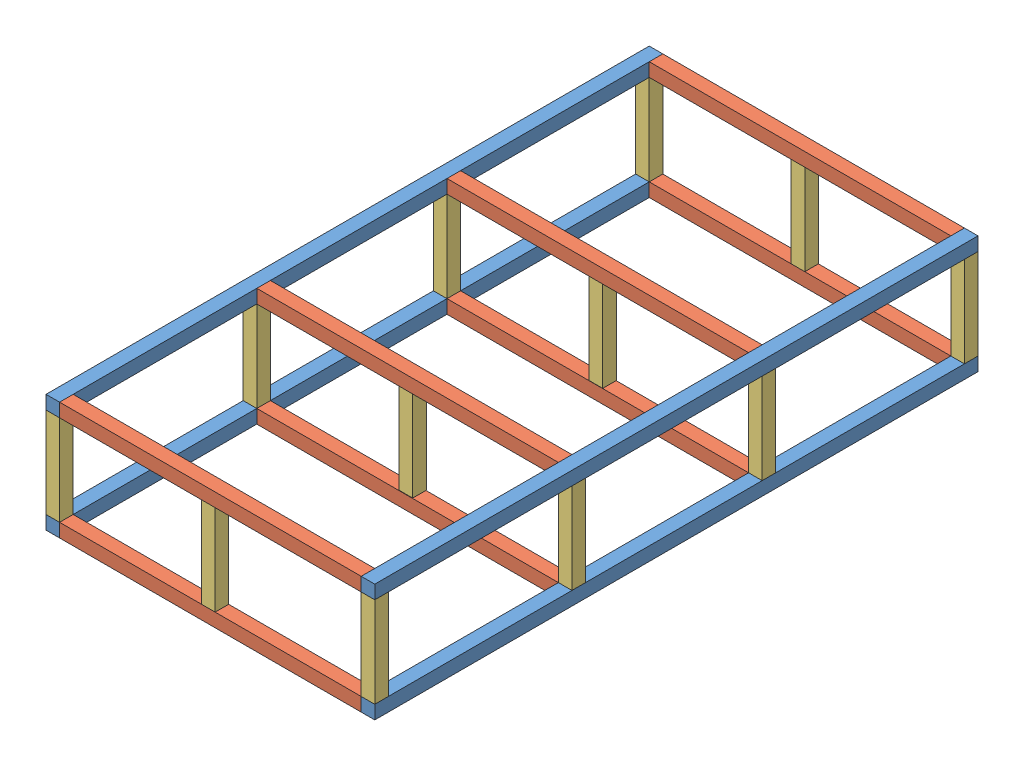
SolidWorks assembly New_assem, configuration Default. Lengths in mm.
Overall size (1090 390 2000).
24 component instances, 3 part files, 21 mates.
Components (placement in the parent):
- 4545_2000-1: 4545_2000 [Default] at (664.3232 958.4643 609.3143) size (45 45 2000)
- 4545_1000-1: 4545_1000 [Default] at (664.3232 958.4643 2564.3143) x (0 0 1) z (-1 0 0) size (45 45 1000)
- 4545_2000-2: 4545_2000 [Default] at (-380.6768 958.4643 609.3143) size (45 45 2000)
- 4545_1000-2: 4545_1000 [Default] at (664.3232 958.4643 609.3143) x (0 0 1) z (-1 0 0) size (45 45 1000)
- 4545_300-1: 4545_300 [Default] at (664.3232 1003.4643 2609.3143) x (1 0 0) z (0 1 0) size (45 45 300)
- 4545_300-2: 4545_300 [Default] at (-380.6768 1003.4643 2609.3143) x (1 0 0) z (0 1 0) size (45 45 300)
- 4545_300-3: 4545_300 [Default] at (664.3232 1003.4643 654.3143) x (1 0 0) z (0 1 0) size (45 45 300)
- 4545_300-4: 4545_300 [Default] at (-380.6768 1003.4643 654.3143) x (1 0 0) z (0 1 0) size (45 45 300)
- 4545_1000-3: 4545_1000 [Default] at (664.3232 1303.4643 609.3143) x (0 0 1) z (-1 0 0) size (45 45 1000)
- 4545_2000-3: 4545_2000 [Default] at (-380.6768 1303.4643 609.3143) size (45 45 2000)
- 4545_1000-4: 4545_1000 [Default] at (664.3232 1303.4643 2564.3143) x (0 0 1) z (-1 0 0) size (45 45 1000)
- 4545_2000-4: 4545_2000 [Default] at (664.3232 1303.4643 609.3143) size (45 45 2000)
- 4545_300-5: 4545_300 [Default] at (664.3232 1003.4643 1955.4889) x (1 0 0) z (0 1 0) size (45 45 300)
- 4545_300-6: 4545_300 [Default] at (664.3232 1003.4643 1324.9073) x (1 0 0) z (0 1 0) size (45 45 300)
- 4545_300-7: 4545_300 [Default] at (-380.6768 1003.4643 1324.9073) x (1 0 0) z (0 1 0) size (45 45 300)
- 4545_300-8: 4545_300 [Default] at (-380.6768 1003.4643 1955.4889) x (1 0 0) z (0 1 0) size (45 45 300)
- 4545_1000-5: 4545_1000 [Default] at (664.3232 958.4643 1910.4889) x (0 0 1) z (-1 0 0) size (45 45 1000)
- 4545_1000-6: 4545_1000 [Default] at (664.3232 958.4643 1279.9073) x (0 0 1) z (-1 0 0) size (45 45 1000)
- 4545_1000-7: 4545_1000 [Default] at (664.3232 1303.4643 1279.9073) x (0 0 1) z (-1 0 0) size (45 45 1000)
- 4545_1000-8: 4545_1000 [Default] at (664.3232 1303.4643 1910.4889) x (0 0 1) z (-1 0 0) size (45 45 1000)
- 4545_300-9: 4545_300 [Default] at (135.0671 1003.4643 654.3143) x (1 0 0) z (0 1 0) size (45 45 300)
- 4545_300-10: 4545_300 [Default] at (135.0671 1003.4643 1324.3143) x (1 0 0) z (0 1 0) size (45 45 300)
- 4545_300-11: 4545_300 [Default] at (135.0671 1003.4643 2609.3143) x (1 0 0) z (0 1 0) size (45 45 300)
- 4545_300-12: 4545_300 [Default] at (135.0671 1003.4643 1954.3143) x (1 0 0) z (0 1 0) size (45 45 300)
Mates (geometry in assembly coordinates):
- Coincident1: coincident anti-aligned: line of 4545_2000-1 through (664.3232 958.4643 2609.3143) axis (0 0 -1); line of 4545_1000-1 through (664.3232 958.4643 2564.3143) axis (0 0 1)
- Coincident2: coincident anti-aligned: line of 4545_2000-1 through (664.3232 1003.4643 2609.3143) axis (0 -1 0); line of 4545_1000-1 through (664.3232 958.4643 2609.3143) axis (0 1 0)
- Coincident3: coincident aligned: line of 4545_1000-1 through (-335.6768 958.4643 2609.3143) axis (0 1 0); line of 4545_2000-2 through (-335.6768 958.4643 2609.3143) axis (0 1 0)
- Coincident4: coincident aligned: line of 4545_1000-1 through (-335.6768 1003.4643 2609.3143) axis (0 0 -1); line of 4545_2000-2 through (-335.6768 1003.4643 2609.3143) axis (0 0 -1)
- Coincident5: coincident anti-aligned: line of 4545_2000-2 through (-335.6768 958.4643 609.3143) axis (0 1 0); line of 4545_1000-2 through (-335.6768 1003.4643 609.3143) axis (0 -1 0)
- Coincident6: coincident anti-aligned: line of 4545_2000-2 through (-335.6768 958.4643 2609.3143) axis (0 0 -1); line of 4545_1000-2 through (-335.6768 958.4643 609.3143) axis (0 0 1)
- Coincident8: coincident anti-aligned: plane of 4545_2000-1 through (664.3232 1003.4643 2609.3143) normal (0 1 0); plane of 4545_300-1 through (664.3232 1003.4643 2609.3143) normal (0 -1 0)
- Coincident9: coincident aligned: line of 4545_2000-1 through (709.3232 1003.4643 2609.3143) axis (0 0 -1); line of 4545_300-1 through (709.3232 1003.4643 2609.3143) axis (0 0 -1)
- Coincident10: coincident anti-aligned: line of 4545_2000-1 through (709.3232 1003.4643 2609.3143) axis (-1 0 0); line of 4545_300-1 through (664.3232 1003.4643 2609.3143) axis (1 0 0)
- Coincident11: coincident anti-aligned: plane of 4545_2000-1 through (664.3232 1003.4643 2609.3143) normal (0 1 0); plane of 4545_300-5 through (664.3232 1003.4643 1955.4889) normal (0 -1 0)
- Coincident12: coincident aligned: line of 4545_2000-1 through (709.3232 1003.4643 2609.3143) axis (0 0 -1); line of 4545_300-5 through (709.3232 1003.4643 1955.4889) axis (0 0 -1)
- Coincident13: coincident anti-aligned: plane of 4545_2000-1 through (664.3232 1003.4643 2609.3143) normal (0 1 0); plane of 4545_300-6 through (664.3232 1003.4643 1324.9073) normal (0 -1 0)
- Coincident14: coincident aligned: line of 4545_2000-1 through (709.3232 1003.4643 2609.3143) axis (0 0 -1); line of 4545_300-6 through (709.3232 1003.4643 1324.9073) axis (0 0 -1)
- Coincident17: coincident anti-aligned: plane of 4545_2000-2 through (-335.6768 958.4643 2609.3143) normal (1 0 0); plane of 4545_1000-5 through (-335.6768 958.4643 1910.4889) normal (-1 0 0)
- Coincident18: coincident aligned: line of 4545_300-8 through (-335.6768 1003.4643 1955.4889) axis (0 0 -1); line of 4545_1000-5 through (-335.6768 1003.4643 1955.4889) axis (0 0 -1)
- Coincident19: coincident anti-aligned: plane of 4545_2000-2 through (-335.6768 958.4643 2609.3143) normal (1 0 0); plane of 4545_1000-6 through (-335.6768 958.4643 1279.9073) normal (-1 0 0)
- Coincident20: coincident aligned: line of 4545_300-7 through (-335.6768 1003.4643 1324.9073) axis (0 0 -1); line of 4545_1000-6 through (-335.6768 1003.4643 1324.9073) axis (0 0 -1)
- Coincident21: coincident: point of 4545_300-7; point of 4545_1000-6
- Coincident22: coincident: point of 4545_300-5; point of 4545_1000-5
- Coincident23: coincident anti-aligned: plane of 4545_1000-2 through (-335.6768 1003.4643 609.3143) normal (0 1 0); plane of 4545_300-9 through (135.0671 1003.4643 654.3143) normal (0 -1 0)
- Coincident24: coincident aligned: line of 4545_1000-2 through (-335.6768 1003.4643 654.3143) axis (1 0 0); line of 4545_300-9 through (135.0671 1003.4643 654.3143) axis (1 0 0)
